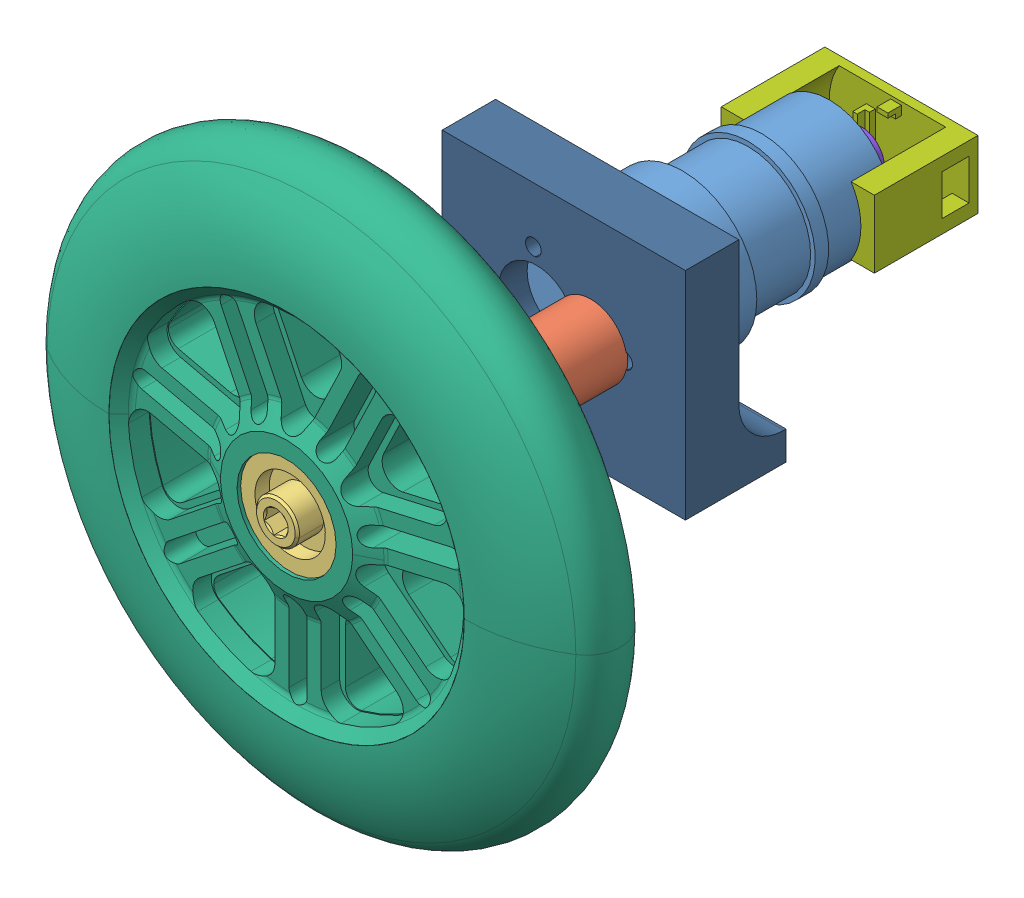
SolidWorks assembly DriveAssemblyRight, configuration Default. Lengths in mm.
Overall size (124.46 124.46 144.88).
11 component instances, 11 part files, 26 mates.
Components (placement in the parent):
- 1400-0032-0032 assembly.STEP-1: 1400-0032-0032 assembly.STEP [Default] at (6.581 -3.5947 -1.114) size (42.17 43 8) (hidden)
- Motor-2: Motor [Default] at (-2.6241 5.961 7.9343) x (0 0 -1) z (0 -1 0) size (70.6 33 33)
- Coupler-1: Coupler [Default] at (3.3759 5.961 25.3343) x (0 0 1) z (-0.88407 -0.467355 0) size (22.5 16 16)
- 595630 assembly.STEP-1: 595630 assembly.STEP [Default] at (-38.3353 -14.4315 51.5475) x (-0.997959 -0.063851 0) z (-0.063851 0.997959 0) size (25.39 31.39 25.39)
- 545579 assembly.STEP-1: 545579 assembly.STEP [Default] at (31.7418 -41.3992 66.5368) x (0.750814 -0.660514 0) z (0.660514 0.750814 0) size (20.57 9.61 20.57)
- 1602-0032-0250 assembly.STEP-1: 1602-0032-0250 assembly.STEP [Default] at (-28.6325 25.9608 25.7882) x (-1 0 0) z (0 -1 0) size (38 7 33.35)
- 3608-0001-0125 assembly.STEP-1: 3608-0001-0125 assembly.STEP [Default] at (-9.1121 15.7426 69.8072) size (124.46 124.46 23.93)
- Encoder_BracketMount_V2-1: Encoder_BracketMount_V2 [Default] at (-2.6241 5.961 -58.6657) x (0 1 0) z (0 0 1) size (15 34 23)
- Encoder_MagnetMount_V2-1: Encoder_MagnetMount_V2 [Default] at (-2.6241 5.961 -49.8657) x (-1 0 0) z (0 0 -1) size (10 10 5)
- 634060-1: 634060 [Default] at (3.3759 5.961 55.6343) x (0 -1 0) z (1 0 0) size (5.71 25.4 6.34)
- MotorMount-1: MotorMount [Default] at (-2.6241 5.961 11.1093) size (54 48 23.2)
Mates (geometry in assembly coordinates):
- Concentric1: concentric anti-aligned: cylinder of 1400-0032-0032 assembly.STEP-1 through (-2.6241 5.961 1.9343) axis (0 0 -1) radius 16; cylinder of Motor-2 through (-2.6241 5.961 7.9343) axis (0 0 1) radius 16.5
- Width1: width anti-aligned: plane of Motor-2 through (-2.6241 5.961 7.9343) normal (0 0 1); plane of 1400-0032-0032 assembly.STEP-1 through (-2.6241 5.961 -12.0657) normal (0 0 -1); plane of Motor-2 through (-2.6241 5.961 -6.0657) normal (0 0 -1); plane of 1400-0032-0032 assembly.STEP-1 through (-2.6241 5.961 1.9343) normal (0 0 1)
- Concentric2: concentric anti-aligned: cylinder of Motor-2 through (3.3759 5.961 20.4343) axis (0 0 1) radius 2.5; cylinder of Coupler-1 through (3.3759 5.961 36.5843) axis (0 0 -1) radius 2.5
- Concentric3: concentric anti-aligned: cylinder of 595630 assembly.STEP-1 through (3.3759 5.961 59.8045) axis (0 0 -1) radius 6.35; cylinder of 545579 assembly.STEP-1 through (3.3759 5.961 52.8195) axis (0 0 1) radius 6.35
- Concentric4: concentric aligned: cylinder of 595630 assembly.STEP-1 through (2.7515 15.7201 54.0895) axis (0 0 1) radius 1.778; circle of 545579 assembly.STEP-1
- Coincident5: coincident anti-aligned: plane of 595630 assembly.STEP-1 through (3.3759 5.961 52.8195) normal (0 0 -1); plane of 545579 assembly.STEP-1 through (-1.5036 5.6488 52.8195) normal (0 0 1)
- Coincident6: coincident aligned: plane of 1400-0032-0032 assembly.STEP-1 through (10.3759 -18.039 1.9343) normal (0 -1 0); plane of 1602-0032-0250 assembly.STEP-1 through (22.3759 -18.039 37.7968) normal (0 -1 0)
- Concentric5: concentric aligned: cylinder of Coupler-1 through (3.3759 5.961 25.3343) axis (0 0 1) radius 3.175; cylinder of 1602-0032-0250 assembly.STEP-1 through (3.3759 5.961 40.0343) axis (0 0 1) radius 3.175
- Concentric8: concentric aligned: cylinder of 1602-0032-0250 assembly.STEP-1 through (3.3759 5.961 62.7573) axis (0 0 -1) radius 5.35; cylinder of 3608-0001-0125 assembly.STEP-1 through (3.3759 5.961 81.8263) axis (0 0 -1) radius 9.5758
- Concentric9: concentric aligned: cylinder of 595630 assembly.STEP-1 through (3.3759 5.961 74.1763) axis (0 0 1) radius 10.9855; cylinder of 3608-0001-0125 assembly.STEP-1 through (3.3759 5.961 74.7626) axis (0 0 1) radius 11
- Coincident10: coincident anti-aligned: plane of 595630 assembly.STEP-1 through (3.3759 5.961 57.8995) normal (0 0 1); plane of 3608-0001-0125 assembly.STEP-1 through (18.0589 5.961 57.8995) normal (0 0 -1)
- Concentric11: concentric anti-aligned: cylinder of Motor-2 through (-2.6241 5.961 7.9343) axis (0 0 1) radius 13.85; cylinder of Encoder_BracketMount_V2-1 through (-2.6241 5.961 -41.6657) axis (0 0 -1) radius 14
- Coincident17: coincident aligned: plane of Motor-2 through (-2.6241 5.961 -44.6657) normal (0 0 -1); plane of Encoder_BracketMount_V2-1 through (-2.6241 5.961 -44.6657) normal (0 0 -1)
- Coincident18: coincident anti-aligned: plane of Motor-2 through (-2.6241 5.961 -46.8657) normal (0 0 -1); plane of Encoder_MagnetMount_V2-1 through (-2.6241 5.961 -46.8657) normal (0 0 1)
- Concentric12: concentric anti-aligned: cylinder of Motor-2 through (-2.6241 5.961 7.9343) axis (0 0 1) radius 1.15; cylinder of Encoder_MagnetMount_V2-1 through (-2.6241 5.961 -46.8657) axis (0 0 -1) radius 1.25
- Distance8: distance = 22.225 mm anti-aligned: plane of 595630 assembly.STEP-1 through (3.3759 5.961 58.8093) normal (0 0 -1); plane of Coupler-1 through (3.3759 5.961 36.5843) normal (0 0 1)
- Coincident22: coincident anti-aligned: plane of Motor-2 through (-2.6241 5.961 20.4343) normal (0 0 1); plane of Coupler-1 through (3.3759 5.961 20.4343) normal (0 0 -1)
- Coincident23: coincident anti-aligned: plane of Coupler-1 through (3.3759 5.961 30.2343) normal (0 0 1); plane of 634060-1 through (3.3759 5.961 30.2343) normal (0 0 -1)
- Concentric14: concentric aligned: cylinder of Coupler-1 through (3.3759 5.961 25.3343) axis (0 0 1) radius 3.175; cylinder of 634060-1 through (3.3759 5.961 23.8843) axis (0 0 1) radius 3.1712
- Distance9: distance = 42.8625 mm aligned: plane of 1602-0032-0250 assembly.STEP-1 through (3.3759 5.961 44.7968) normal (0 0 1); plane of 1400-0032-0032 assembly.STEP-1 through (-2.6241 5.961 1.9343) normal (0 0 1)
- Parallel3: parallel aligned: plane of 1400-0032-0032 assembly.STEP-1 through (-21.6241 -18.039 1.9343) normal (-1 0 0); plane of Encoder_BracketMount_V2-1 through (-19.6241 5.961 -41.6657) normal (-1 0 0)
- Parallel4: parallel anti-aligned: plane of 1400-0032-0032 assembly.STEP-1 through (-21.6241 -18.039 1.9343) normal (-1 0 0); plane of Motor-2 through (4.8759 5.961 12.4343) normal (1 0 0)
- Parallel5: parallel aligned: plane of 1602-0032-0250 assembly.STEP-1 through (-15.6241 -8.7963 37.7968) normal (-1 0 0); plane of 3608-0001-0125 assembly.STEP-1 through (-3.0249 -7.3304 81.8263) normal (-1 0 0)
- Concentric15: concentric aligned: cylinder of Motor-2 through (-2.6241 5.961 7.9343) axis (0 0 1) radius 16.5; cylinder of MotorMount-1 through (-2.6241 5.961 2.4343) axis (0 0 1) radius 17
- Coincident24: coincident anti-aligned: plane of Motor-2 through (-2.6241 5.961 7.9343) normal (0 0 1); plane of MotorMount-1 through (-2.6241 5.961 7.9343) normal (0 0 -1)
- Coincident26: coincident aligned: plane of 1400-0032-0032 assembly.STEP-1 through (-15.6241 -18.039 1.9343) normal (0 -1 0); plane of MotorMount-1 through (-26.6241 -18.039 14.2843) normal (0 -1 0)
